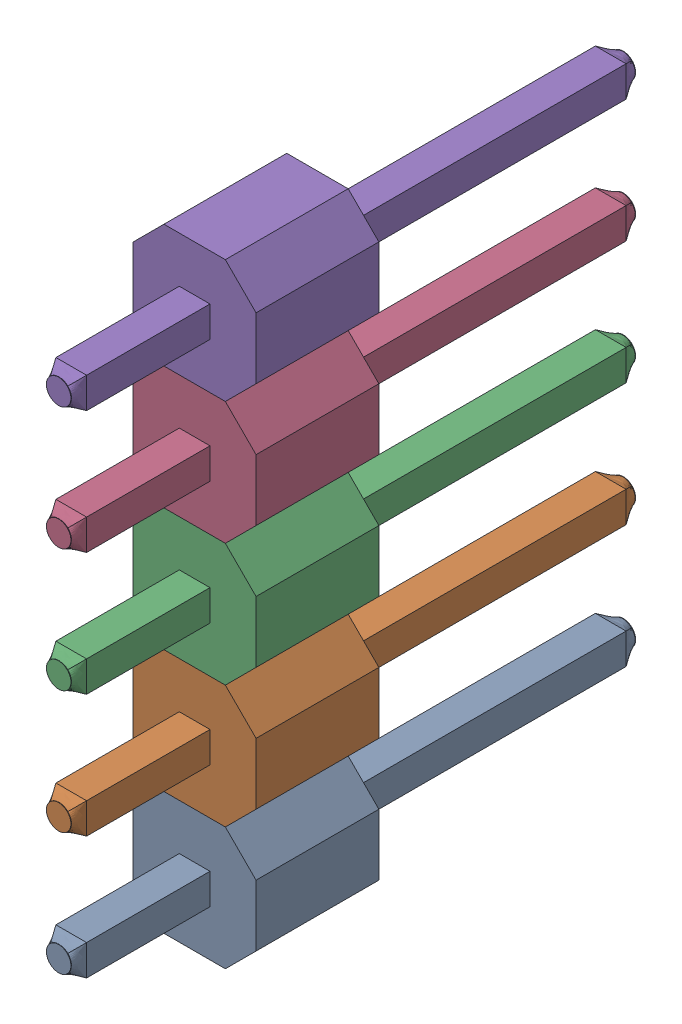
SolidWorks assembly Male Header 5 Pin, configuration Default. Lengths in mm.
Overall size (2.54 12.7 11.76).
5 component instances, 1 part files, 0 mates.
Components (placement in the parent):
- Male Header Pin-1: Male Header Pin [Default] at (-3.2163 0.3587 1.4535) size (2.54 2.54 11.76)
- Male Header Pin-2: Male Header Pin [Default] at (-3.2163 2.8987 1.4535) size (2.54 2.54 11.76)
- Male Header Pin-3: Male Header Pin [Default] at (-3.2163 5.4387 1.4535) size (2.54 2.54 11.76)
- Male Header Pin-4: Male Header Pin [Default] at (-3.2163 7.9787 1.4535) size (2.54 2.54 11.76)
- Male Header Pin-5: Male Header Pin [Default] at (-3.2163 10.5187 1.4535) size (2.54 2.54 11.76)
